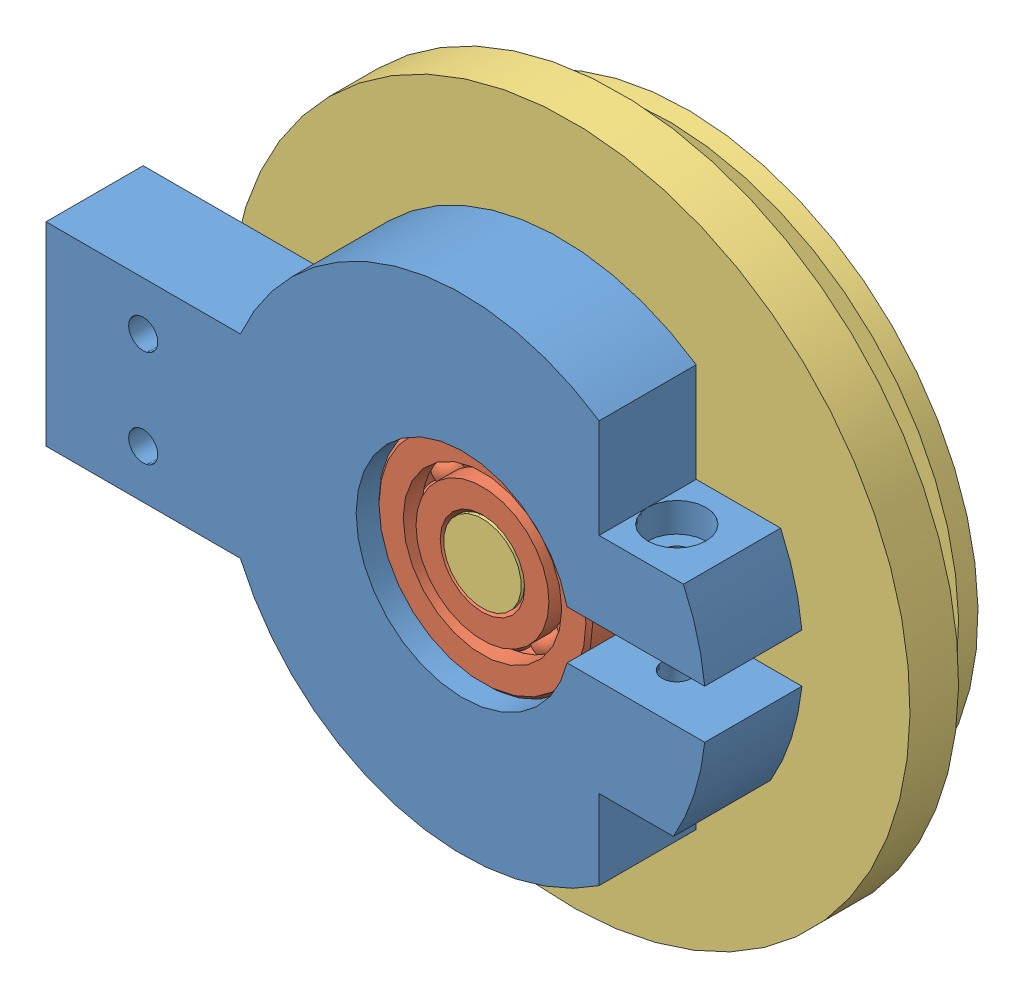
SolidWorks assembly elbow_joint, configuration Default. Lengths in mm.
Overall size (99.72 95.06 23).
3 component instances, 3 part files, 4 mates.
Components (placement in the parent):
- joint_upper_22mmID-1: joint_upper_22mmID [Default] at (27.3835 39.5429 47.8644) size (67.79 50 10)
- 22mm_BALL BEARING-1: 22mm_BALL BEARING [5972K91] at (27.3835 39.5429 52.3644) size (22 22 7)
- joint_lower_8mmOD-1: joint_lower_8mmOD [Default] at (27.3835 39.5429 55.8644) x (-0.387907 -0.921699 0) z (0 0 -1) size (70 78.74 22)
Mates (geometry in assembly coordinates):
- Concentric1: concentric anti-aligned: cylinder of joint_upper_22mmID-1 through (27.3835 39.5429 57.8644) axis (0 0 -1) radius 11; cylinder of 22mm_BALL BEARING-1 through (27.3835 39.5429 55.8644) axis (0 0 1) radius 11
- Distance2: distance = 1 mm aligned: plane of joint_upper_22mmID-1 through (27.3835 39.5429 47.8644) normal (0 0 -1); plane of 22mm_BALL BEARING-1 through (27.3835 50.1929 48.8644) normal (0 0 -1)
- Concentric2: concentric aligned: cylinder of 22mm_BALL BEARING-1 through (27.3835 39.5429 55.8644) axis (0 0 1) radius 4; cylinder of joint_lower_8mmOD-1 through (27.3835 39.5429 48.8644) axis (0 0 1) radius 4.1
- Coincident3: coincident anti-aligned: plane of 22mm_BALL BEARING-1 through (27.3835 43.8929 48.8644) normal (0 0 -1); plane of joint_lower_8mmOD-1 through (27.3835 39.5429 48.8644) normal (0 0 1)
